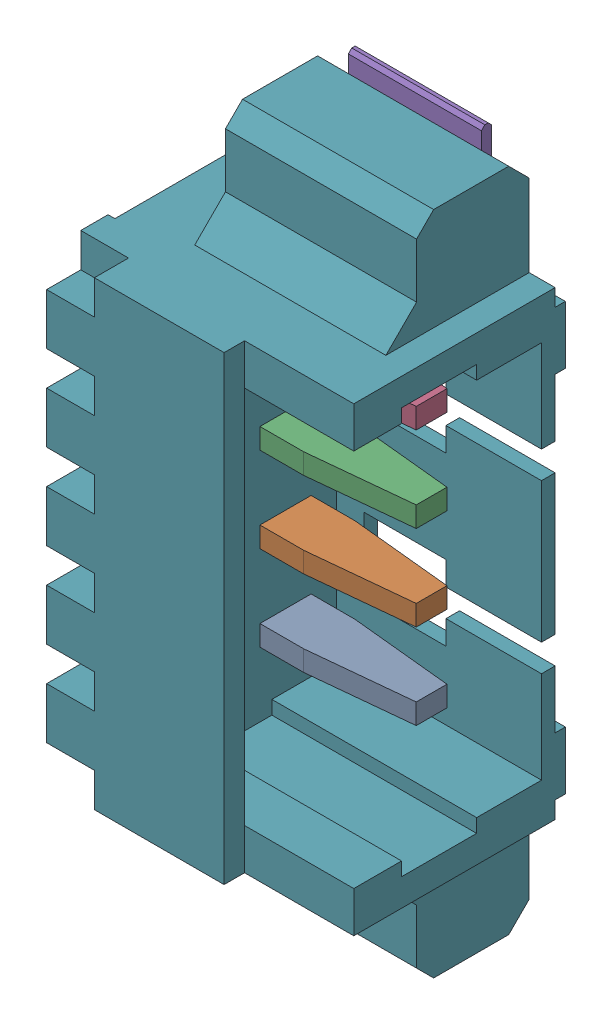
SolidWorks assembly J7, configuration Default. Lengths in mm.
Overall size (5.4 9.75 3.41).
8 component instances, 3 part files, 0 mates.
Components (placement in the parent):
- 653104131822-1: 653104131822 [Default] at (138.95 26.3999 1.69) x (0 1 0) z (0 0 1) size (9.75 5.4 3.41)
  - 6531xx131822_PIN_2-1: 6531xx131822_PIN_2 [Default] at (-1.875 2.7 -0.425) x (1 0 0) z (0 -1 0) size (0.3 1.48 4.54)
  - 6531xx131822_PIN_2-2: 6531xx131822_PIN_2 [Default] at (-0.625 2.7 -0.425) x (1 0 0) z (0 -1 0) size (0.3 1.48 4.54)
  - 6531xx131822_PIN_2-3: 6531xx131822_PIN_2 [Default] at (0.625 2.7 -0.425) x (1 0 0) z (0 -1 0) size (0.3 1.48 4.54)
  - 6531xx131822_PIN_2-4: 6531xx131822_PIN_2 [Default] at (1.875 2.7 -0.425) x (1 0 0) z (0 -1 0) size (0.3 1.48 4.54)
  - 6531xx131822_PIN_FLANGE_2-1: 6531xx131822_PIN_FLANGE_2 [Default] at (3.75 -0.045 -1.05) size (1.25 1.95 1.4)
  - 6531xx131822_PIN_FLANGE_2-2: 6531xx131822_PIN_FLANGE_2 [Default] at (-3.75 -0.045 -1.05) x (-1 0 0) z (0 0 1) size (1.25 1.95 1.4)
  - 653104131822-1: 653104131822 [Default] at origin size (9.75 4.2 3.4)
